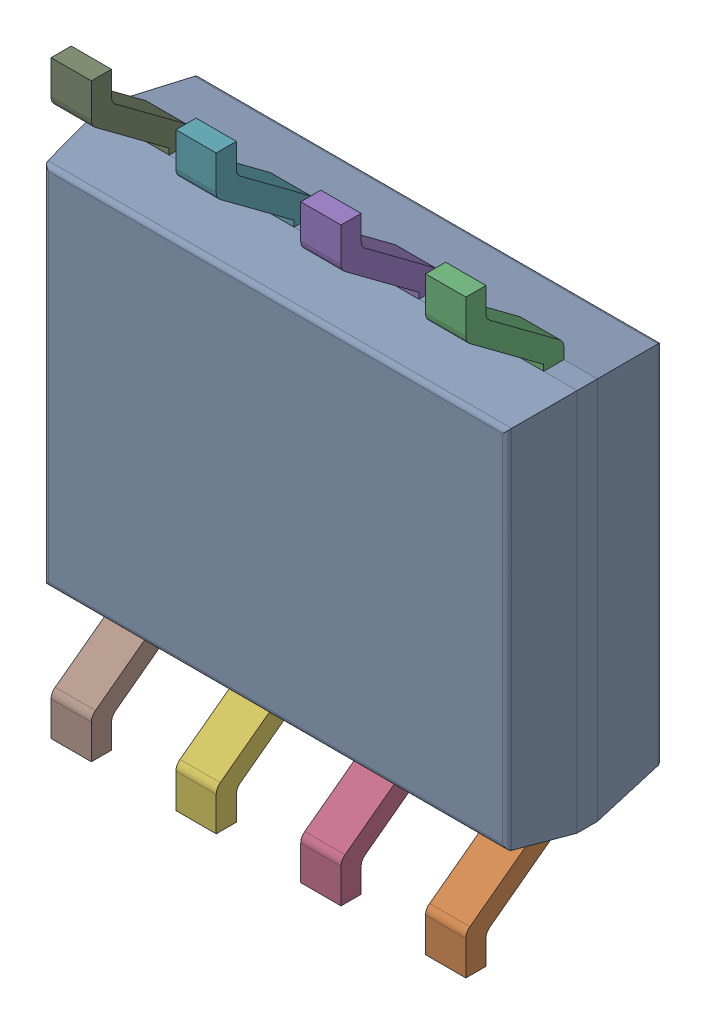
SolidWorks assembly IC2, configuration Default. Lengths in mm.
Overall size (4.9 6 1.75).
3 component instances, 2 part files, 0 mates.
Components (placement in the parent):
- 10172115792-1: 10172115792 [Default] at (115.062 70.612 -1.0914) x (0 1 0) z (0 0 -1) size (6 4.9 1.75)
  - Body-0-1: Body-0 [Default] at origin size (3.9 4.9 1.57)
  - PinsArrayLR-1-1: PinsArrayLR-1 [Default] at origin size (6 4.22 1)
